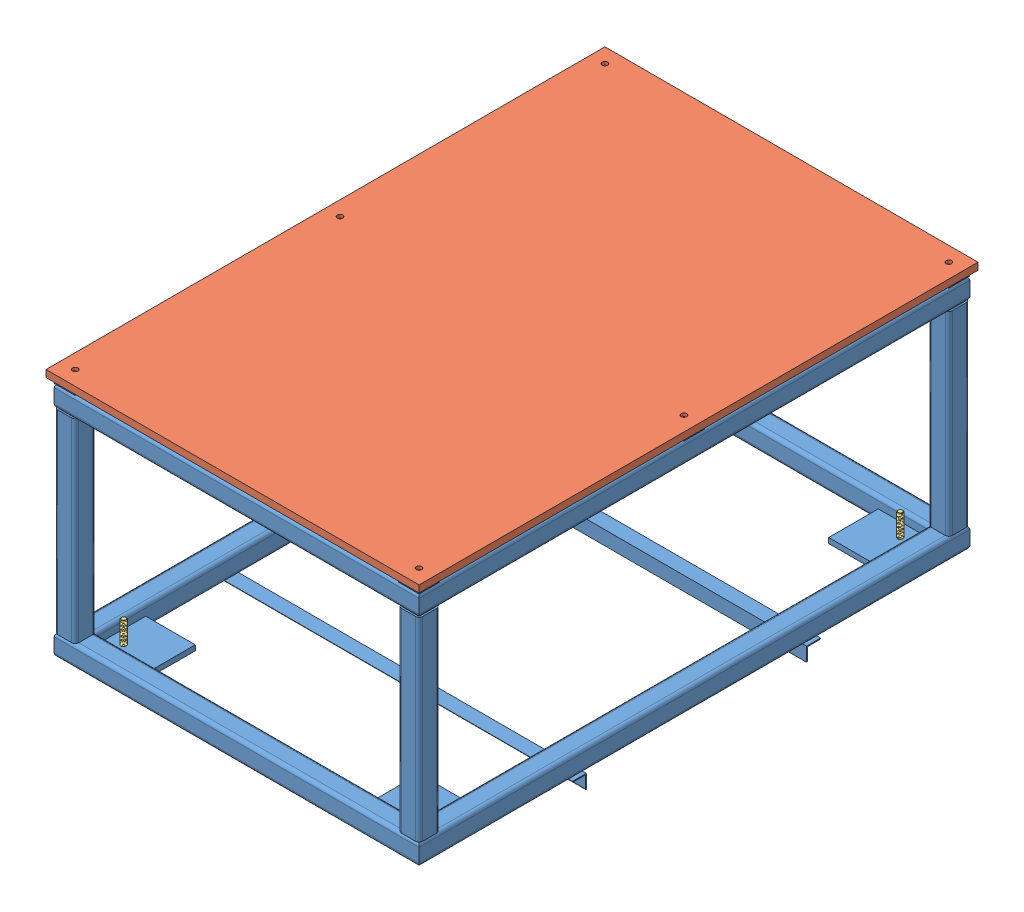
SolidWorks assembly TEST-BBB-AA, configuration Default. Lengths in mm.
Overall size (1355 977.03 2030).
6 component instances, 3 part files, 6 mates.
Components (placement in the parent):
- TEST-BBB-AB-1: TEST-BBB-AB [Default<As Machined>] at (584.0128 1612.7119 1579.6915) size (1339.8 929.4 2000.2)
- TEST-BBB-AC-1: TEST-BBB-AC [Default] at (584.0128 1638.1119 1579.6915) x (0 0 -1) z (-1 0 0) size (2030 25.4 1355)
- 6111K257_SWIVEL LEVELING MOUNT-1: 6111K257_SWIVEL LEVELING MOUNT [Default] at (172.6128 661.0826 705.7915) size (76.2 193.68 76.2)
- 6111K257_SWIVEL LEVELING MOUNT-2: 6111K257_SWIVEL LEVELING MOUNT [Default] at (1245.4128 661.0826 705.7915) size (76.2 193.68 76.2)
- 6111K257_SWIVEL LEVELING MOUNT-3: 6111K257_SWIVEL LEVELING MOUNT [Default] at (1245.4128 661.0826 2453.5915) size (76.2 193.68 76.2)
- 6111K257_SWIVEL LEVELING MOUNT-4: 6111K257_SWIVEL LEVELING MOUNT [Default] at (172.6128 661.0826 2453.5915) size (76.2 193.68 76.2)
Mates (geometry in assembly coordinates):
- Coincident1: coincident anti-aligned: plane of TEST-BBB-AB-1 through (584.0128 1612.7119 1579.6915) normal (0 1 0); plane of TEST-BBB-AC-1 through (584.0128 1612.7119 1579.6915) normal (0 -1 0)
- Coincident2: coincident anti-aligned: plane of TEST-BBB-AB-1 through (584.0128 1612.7119 1579.6915) normal (0 0 1); plane of TEST-BBB-AC-1 through (584.0128 1638.1119 1579.6915) normal (0 0 -1)
- Coincident3: coincident anti-aligned: plane of TEST-BBB-AB-1 through (584.0128 1612.7119 1579.6915) normal (1 0 0); plane of TEST-BBB-AC-1 through (584.0128 1638.1119 1579.6915) normal (-1 0 0)
- Coincident4: coincident: line of TEST-BBB-AB-1 through (172.6128 753.1576 655.7915) axis (0 0 1); plane of 6111K257_SWIVEL LEVELING MOUNT-1 through (172.6128 661.0826 705.7915) normal (1 0 0)
- Coincident5: coincident: line of TEST-BBB-AB-1 through (122.6128 753.1576 705.7915) axis (1 0 0); plane of 6111K257_SWIVEL LEVELING MOUNT-1 through (172.6128 661.0826 705.7915) normal (0 0 1)
- Coincident6: coincident anti-aligned: plane of TEST-BBB-AB-1 through (584.0128 753.1576 1579.6915) normal (0 -1 0); plane of 6111K257_SWIVEL LEVELING MOUNT-1 through (172.6128 753.1576 722.2893) normal (0 1 0)
